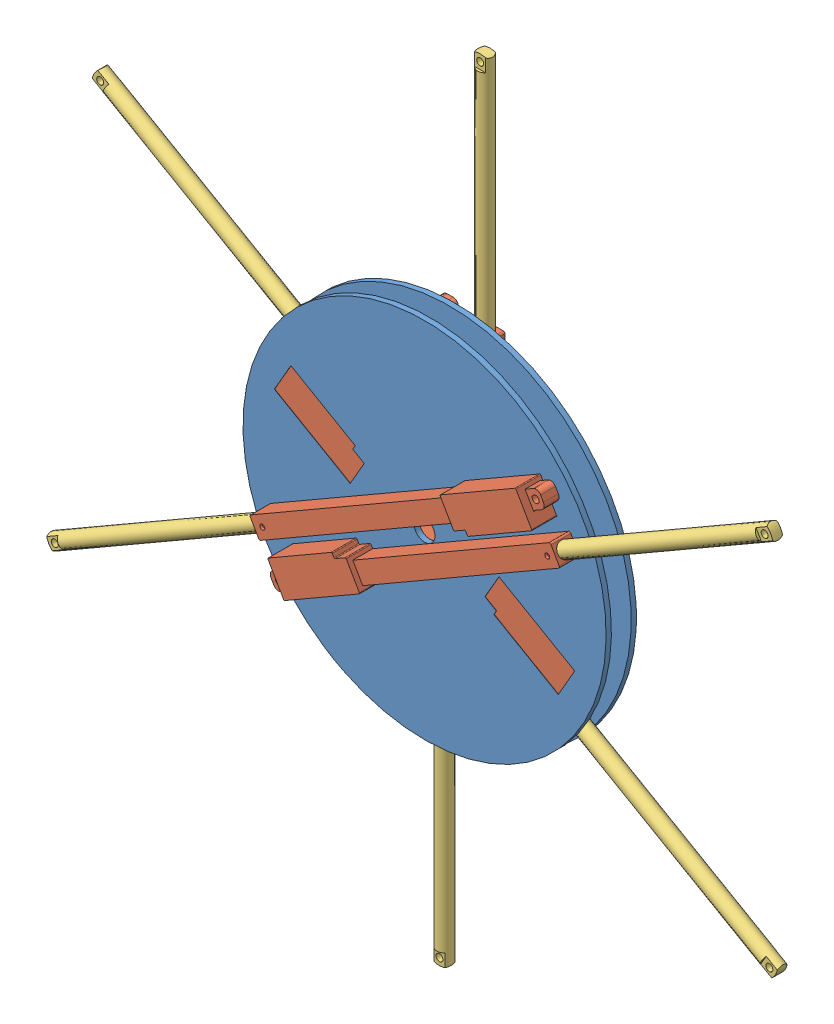
SolidWorks assembly wheel without end plates, configuration Default. Lengths in mm.
Overall size (445.79 490.68 48.35).
20 component instances, 3 part files, 21 mates.
Components (placement in the parent):
- middle plate-4: middle plate [Default] at (77.1755 122.1044 159.9255) size (220 220 3.17)
- actuator assembly-1: actuator assembly [Default] at (227.3666 91.0795 302.7677) x (0.866025 -0.5 0) z (0 0 -1) size (347.34 20 18)
  - actuator body-2: actuator body [Default] at (-243.5818 29.8772 135.2547) size (200 20 18)
  - actuator arm-2: actuator arm [Default] at (-382.5818 40.3772 135.2547) x (1 0 0) z (0 0 -1) size (147.34 9 9)
- actuator assembly-2: actuator assembly [Default] at (-73.0157 153.1293 302.7677) x (-0.866025 0.5 0) z (0 0 -1) size (347.34 20 18)
  - actuator body-2: actuator body [Default] at (-243.5818 29.8772 135.2547) size (200 20 18)
  - actuator arm-2: actuator arm [Default] at (-382.5818 40.3772 135.2547) x (1 0 0) z (0 0 -1) size (147.34 9 9)
- middle plate-3: middle plate [Default] at (77.1755 122.1044 175.1005) x (-0.5 -0.866025 0) z (0 0 1) size (220 220 3.17)
- actuator assembly-3: actuator assembly [Default] at (-24.7885 7.5475 317.9427) x (-0.866025 -0.5 0) z (0 0 -1) size (347.34 20 18)
  - actuator body-2: actuator body [Default] at (-243.5818 29.8772 135.2547) size (200 20 18)
  - actuator arm-2: actuator arm [Default] at (-382.5818 40.3772 135.2547) x (1 0 0) z (0 0 -1) size (147.34 9 9)
- actuator assembly-4: actuator assembly [Default] at (179.1394 236.6613 317.9427) x (0.866025 0.5 0) z (0 0 -1) size (347.34 20 18)
  - actuator body-2: actuator body [Default] at (-243.5818 29.8772 135.2547) size (200 20 18)
  - actuator arm-2: actuator arm [Default] at (-382.5818 40.3772 135.2547) x (1 0 0) z (0 0 -1) size (147.34 9 9)
- actuator assembly-5: actuator assembly [Default] at (28.9483 267.6862 287.5927) x (0 1 0) z (0 0 -1) size (347.34 20 18)
  - actuator body-2: actuator body [Default] at (-243.5818 29.8772 135.2547) size (200 20 18)
  - actuator arm-2: actuator arm [Default] at (-382.5818 40.3772 135.2547) x (1 0 0) z (0 0 -1) size (147.34 9 9)
- actuator assembly-6: actuator assembly [Default] at (125.4027 -23.4775 287.5927) x (0 -1 0) z (0 0 -1) size (347.34 20 18)
  - actuator body-2: actuator body [Default] at (-243.5818 29.8772 135.2547) size (200 20 18)
  - actuator arm-2: actuator arm [Default] at (-382.5818 40.3772 135.2547) x (1 0 0) z (0 0 -1) size (147.34 9 9)
Mates (geometry in assembly coordinates):
- Coincident1: coincident anti-aligned: plane of middle plate-4 through (77.6005 122.8405 161.513) normal (0.5 0.866025 0); plane of actuator assembly-1/actuator body-2 through (-7.27 171.8405 158.513) normal (-0.5 -0.866025 0)
- Coincident2: coincident anti-aligned: plane of middle plate-4 through (157.7158 75.6044 161.513) normal (-0.866025 0.5 0); plane of actuator assembly-1/actuator body-2 through (166.8908 91.4959 158.513) normal (0.866025 -0.5 0)
- Coincident3: coincident anti-aligned: plane of middle plate-4 through (77.1755 122.1044 161.513) normal (0 0 1); plane of actuator assembly-1/actuator body-2 through (1.48 186.9959 161.513) normal (0 0 -1)
- Coincident4: coincident anti-aligned: plane of middle plate-4 through (-3.3649 168.6044 161.513) normal (0.866025 -0.5 0); plane of actuator assembly-2/actuator body-2 through (-12.5399 152.7128 158.513) normal (-0.866025 0.5 0)
- Coincident5: coincident anti-aligned: plane of middle plate-4 through (76.7505 121.3683 161.513) normal (-0.5 -0.866025 0); plane of actuator assembly-2/actuator body-2 through (161.621 72.3683 158.513) normal (0.5 0.866025 0)
- Coincident6: coincident anti-aligned: plane of middle plate-4 through (77.1755 122.1044 161.513) normal (0 0 1); plane of actuator assembly-2/actuator body-2 through (152.871 57.2128 161.513) normal (0 0 -1)
- Coincident17: coincident anti-aligned: plane of actuator assembly-2/actuator body-2 through (-12.5399 152.7128 158.513) normal (-0.866025 0.5 0); plane of middle plate-3 through (-3.3649 168.6044 176.688) normal (0.866025 -0.5 0)
- Coincident18: coincident anti-aligned: plane of actuator assembly-2/actuator body-2 through (161.621 72.3683 158.513) normal (0.5 0.866025 0); plane of middle plate-3 through (76.7505 121.3683 176.688) normal (-0.5 -0.866025 0)
- Coincident19: coincident anti-aligned: plane of actuator assembly-2/actuator body-2 through (152.871 57.2128 173.513) normal (0 0 1); plane of middle plate-3 through (77.1755 122.1044 173.513) normal (0 0 -1)
- Coincident20: coincident anti-aligned: plane of middle plate-3 through (-3.3649 75.6044 176.688) normal (0.866025 0.5 0); plane of actuator assembly-3/actuator body-2 through (5.8101 59.7128 173.688) normal (-0.866025 -0.5 0)
- Coincident21: coincident anti-aligned: plane of middle plate-3 through (87.6005 104.0477 176.688) normal (-0.5 0.866025 0); plane of actuator assembly-3/actuator body-2 through (172.471 153.0477 173.688) normal (0.5 -0.866025 0)
- Coincident22: coincident anti-aligned: plane of middle plate-3 through (77.1755 122.1044 176.688) normal (0 0 1); plane of actuator assembly-3/actuator body-2 through (171.221 155.2128 176.688) normal (0 0 -1)
- Coincident23: coincident anti-aligned: plane of middle plate-3 through (157.7158 168.6044 176.688) normal (-0.866025 -0.5 0); plane of actuator assembly-4/actuator body-2 through (148.5408 184.4959 173.688) normal (0.866025 0.5 0)
- Coincident24: coincident anti-aligned: plane of middle plate-3 through (76.7505 122.8405 176.688) normal (-0.5 0.866025 0); plane of actuator assembly-4/actuator body-2 through (-8.12 73.8405 173.688) normal (0.5 -0.866025 0)
- Coincident25: coincident anti-aligned: plane of middle plate-3 through (77.1755 122.1044 176.688) normal (0 0 1); plane of actuator assembly-4/actuator body-2 through (-16.87 88.9959 176.688) normal (0 0 -1)
- Coincident26: coincident anti-aligned: plane of middle plate-4 through (76.3255 122.1044 161.513) normal (-1 0 0); plane of actuator assembly-5/actuator body-2 through (76.3255 24.1044 143.338) normal (1 0 0)
- Coincident27: coincident anti-aligned: plane of middle plate-4 through (77.1755 215.1044 161.513) normal (0 -1 0); plane of actuator assembly-5/actuator body-2 through (58.8255 215.1044 143.338) normal (0 1 0)
- Coincident28: coincident anti-aligned: plane of middle plate-4 through (77.1755 122.1044 158.338) normal (0 0 -1); plane of actuator assembly-5/actuator body-2 through (58.8255 24.1044 158.338) normal (0 0 1)
- Coincident29: coincident anti-aligned: plane of middle plate-4 through (77.1755 82.1044 161.513) normal (0 -1 0); plane of actuator assembly-6/actuator body-2 through (95.5255 82.1044 143.338) normal (0 1 0)
- Coincident30: coincident anti-aligned: plane of middle plate-4 through (78.0255 122.1044 161.513) normal (1 0 0); plane of actuator assembly-6/actuator body-2 through (78.0255 220.1044 143.338) normal (-1 0 0)
- Coincident31: coincident anti-aligned: plane of middle plate-4 through (77.1755 122.1044 158.338) normal (0 0 -1); plane of actuator assembly-6/actuator body-2 through (95.5255 220.1044 158.338) normal (0 0 1)
